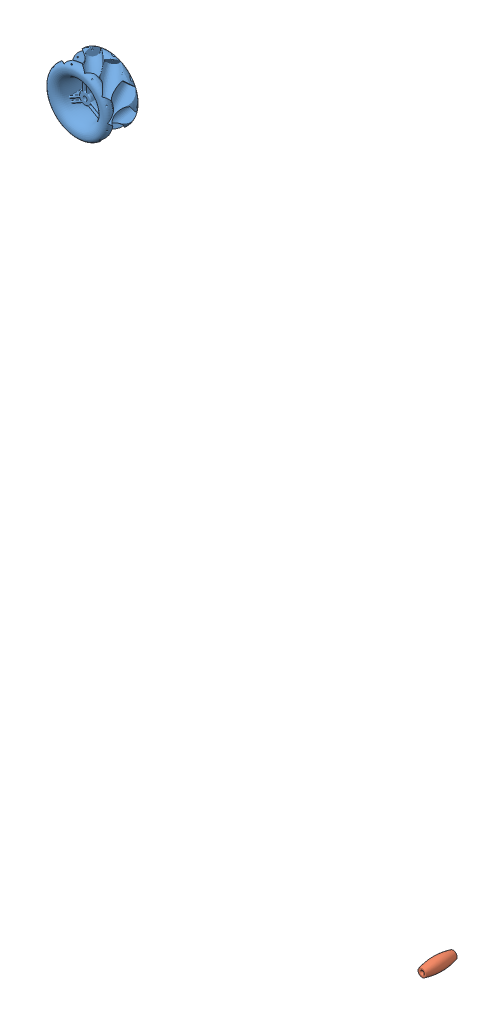
SolidWorks assembly 装配体2, configuration 默认. Lengths in mm.
Overall size (645.36 548.57 226.98).
2 component instances, 2 part files, 0 mates.
Components (placement in the parent):
- 轮子1-1: 轮子1 [默认] at (-128.3873 -63.3178 55.8) size (75.6 75.6 39.6)
- 滚子-2: 滚子 [默认] at (265.3382 -636.1834 245.7015) size (14.4 14.39 37.08)
